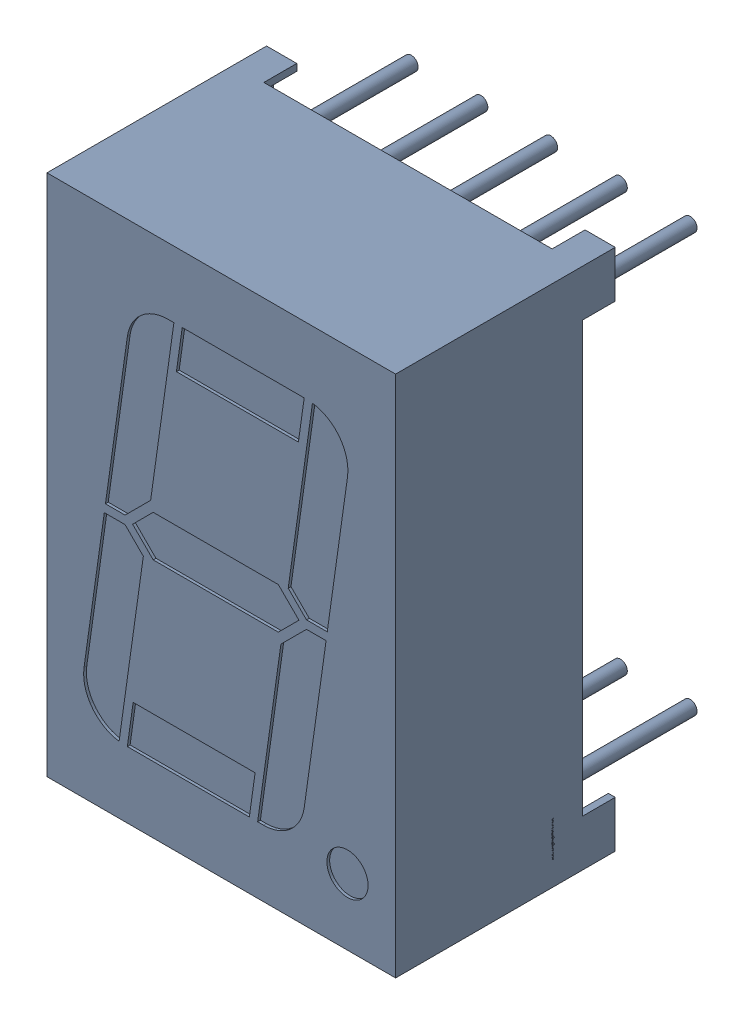
SolidWorks assembly SW3dPS-Disp_SA56-11_2, configuration Default. Lengths in mm.
Overall size (12.7 19.05 12).
2 component instances, 1 part files, 0 mates.
Components (placement in the parent):
- SW3dPS-Disp_SA56-11_Open_CASCADE_STEP_translator_6.2_78.2_2-1: SW3dPS-Disp_SA56-11_Open_CASCADE_STEP_translator_6.2_78.2_2 [Default] at origin size (12.7 19.05 12)
  - SW3dPS-Disp_SA56-11_Disp_SA56-12-1: SW3dPS-Disp_SA56-11_Disp_SA56-12 [Default] at (5.0801 7.6201 8.0327) x (1 0 0) z (0 -1 0) size (12.7 12 19.05)
